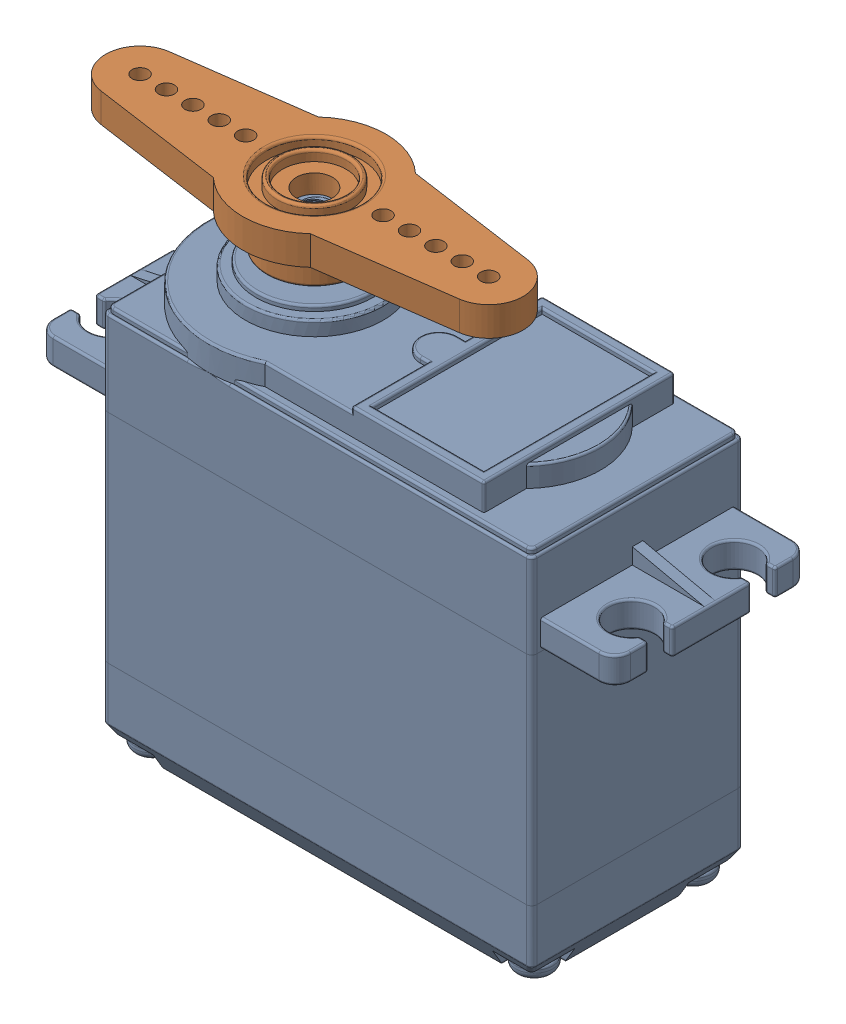
SolidWorks assembly MG996R, configuration Predeterminado. Lengths in mm.
Overall size (57.27 47.1 20).
2 component instances, 2 part files, 2 mates.
Components (placement in the parent):
- Servo MG996R-1: Servo MG996R [Predeterminado] at (3.5621 -14.5001 10) size (54.5 44.55 20)
- Brazo de servo MG996R - Estrella 2-1: Brazo de servo MG996R - Estrella 2 [Predeterminado] at (-6.6879 25.0999 10) x (-0.999996 0 -0.002942) z (-0.002942 0 0.999996) size (39.5 5.95 13.5)
Mates (geometry in assembly coordinates):
- Concéntrica1: concentric anti-aligned: circle of MG996R Motor-1; circle of 2-star horn-1
- Coincidente1: coincident anti-aligned: plane of MG996R Motor-1 through (3.5621 22.3499 10) normal (0 1 0); plane of 2-star horn-1 through (-6.6879 22.3499 10) normal (0 -1 0)
